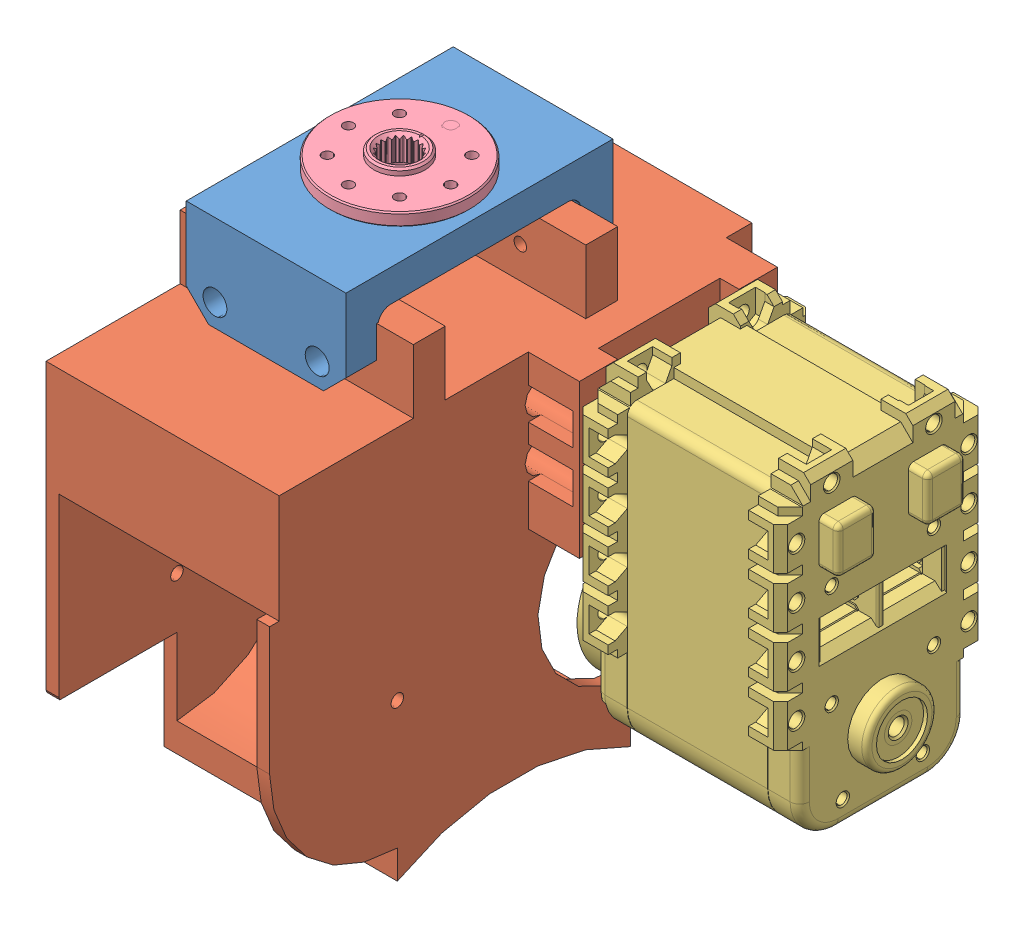
SolidWorks assembly Link8, configuration Default. Lengths in mm.
Overall size (79.67 81 77).
4 component instances, 4 part files, 9 mates.
Components (placement in the parent):
- GripperAttachment-1: GripperAttachment [Default] at (-42.0664 40.1337 50.0699) size (25 15 41.8)
- supporter_cut_36_5-1: supporter_cut_36_5 [Default] at (-45.8164 38.6337 108.0699) x (0 -1 0) z (0 0 1) size (71.5 44.5 77)
- AX-12A-1: AX-12A [Default] at (12.6836 1.1337 53.5699) x (0 0 -1) z (-1 0 0) size (32 50.04 40.25)
- HN07-N101-1: HN07-N101 [Default] at (-29.5664 57.1337 70.9699) x (-1 0 0) z (0 0 1) size (22 5.85 22)
Mates (geometry in assembly coordinates):
- Concentric1: concentric anti-aligned: circle of supporter_cut_36_5-1; circle of AX-12A-1
- Concentric2: concentric anti-aligned: circle of supporter_cut_36_5-1; circle of AX-12A-1
- Coincident1: coincident anti-aligned: plane of supporter_cut_36_5-1 through (-6.3164 38.6337 108.0699) normal (1 0 0); plane of AX-12A-1 through (-6.3164 1.1337 53.5699) normal (-1 0 0)
- Concentric3: concentric aligned: circle of GripperAttachment-1; circle of supporter_cut_36_5-1
- Concentric4: concentric aligned: circle of GripperAttachment-1; circle of supporter_cut_36_5-1
- Coincident2: coincident anti-aligned: plane of GripperAttachment-1 through (-42.0664 40.1337 55.0699) normal (0 0 1); plane of supporter_cut_36_5-1 through (-11.3164 38.6337 55.0699) normal (0 0 -1)
- Concentric5: concentric: circle of GripperAttachment-1; circle of HN07-N101-1
- Concentric6: concentric: circle of GripperAttachment-1; circle of HN07-N101-1
- Coincident3: coincident anti-aligned: plane of GripperAttachment-1 through (-42.0664 55.1337 55.0699) normal (0 1 0); plane of HN07-N101-1 through (-29.5664 55.1337 70.9699) normal (0 -1 0)
